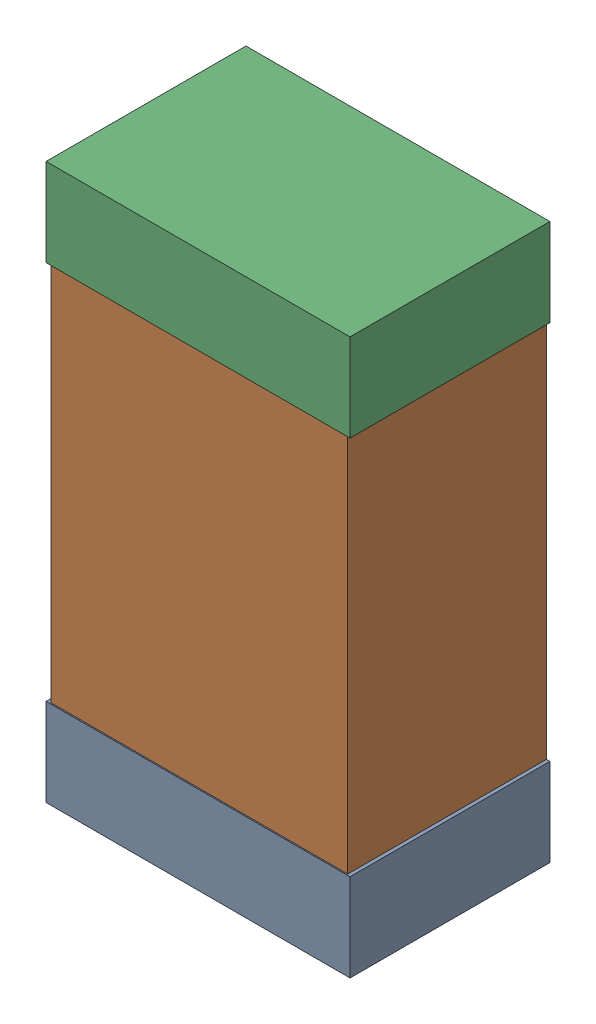
SolidWorks assembly C4Kanaloa_v2.0.0_Motor, configuration Default. Lengths in mm.
Overall size (1.3 2.38 0.85).
6 component instances, 2 part files, 0 mates.
Components (placement in the parent):
- 330415056-1: 330415056 [Default] at (87.376 119.65 0) size (1.3 0.38 0.85)
  - Extruded_2-1: Extruded_2 [Default] at origin size (1.3 0.38 0.85)
- 334787376-1: 334787376 [Default] at (87.376 120.65 0) size (1.27 2.2 0.85)
  - Extruded_16-1: Extruded_16 [Default] at origin size (1.27 2.2 0.85)
- 330415056-2: 330415056 [Default] at (87.376 121.65 0) size (1.3 0.38 0.85)
  - Extruded_2-1: Extruded_2 [Default] at origin size (1.3 0.38 0.85)
